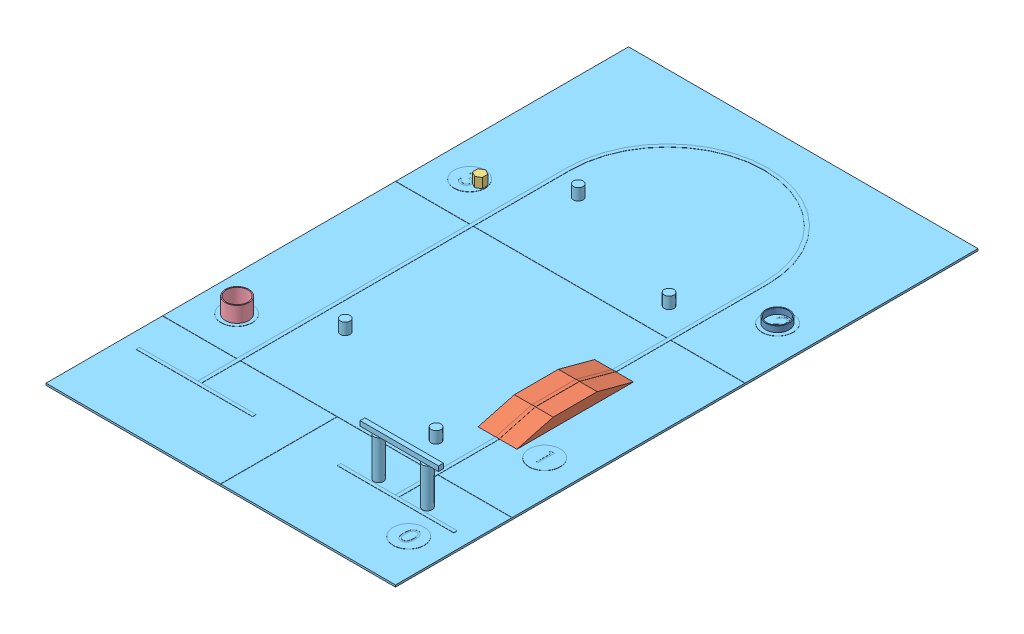
SolidWorks assembly Assem2, configuration Default. Lengths in mm.
Overall size (1800 235 3000).
7 component instances, 6 part files, 0 mates.
Components (placement in the parent):
- Test Place-1: Test Place [預設] at (958.8982 1640.0374 3364.0427) size (1800 235 3000)
  - Ball Bucket 1-1: Ball Bucket 1 [Default] at (717.4068 1.6554 -1749.596) size (120 30 120)
  - Hill-1: Hill [Default] at (508.2919 0.7332 -517.1834) x (0 0 -1) z (1 0 0) size (600.52 51 200)
  - Hexagonal-1: Hexagonal [Default] at (-667.9429 1 -1603.7384) x (0.876055 0 0.482211) z (-0.482211 0 0.876055) size (57.74 50 50)
  - Ball-1: Ball [預設] at (507.5568 37.3778 66.0375) size (39 39 39) (hidden)
  - Ball Bucket 2-2: Ball Bucket 2 [預設] at (-715.465 1.322 -399.5913) size (120 80 120)
  - Track-2: Track [Default] at origin size (1800 235 3000)
